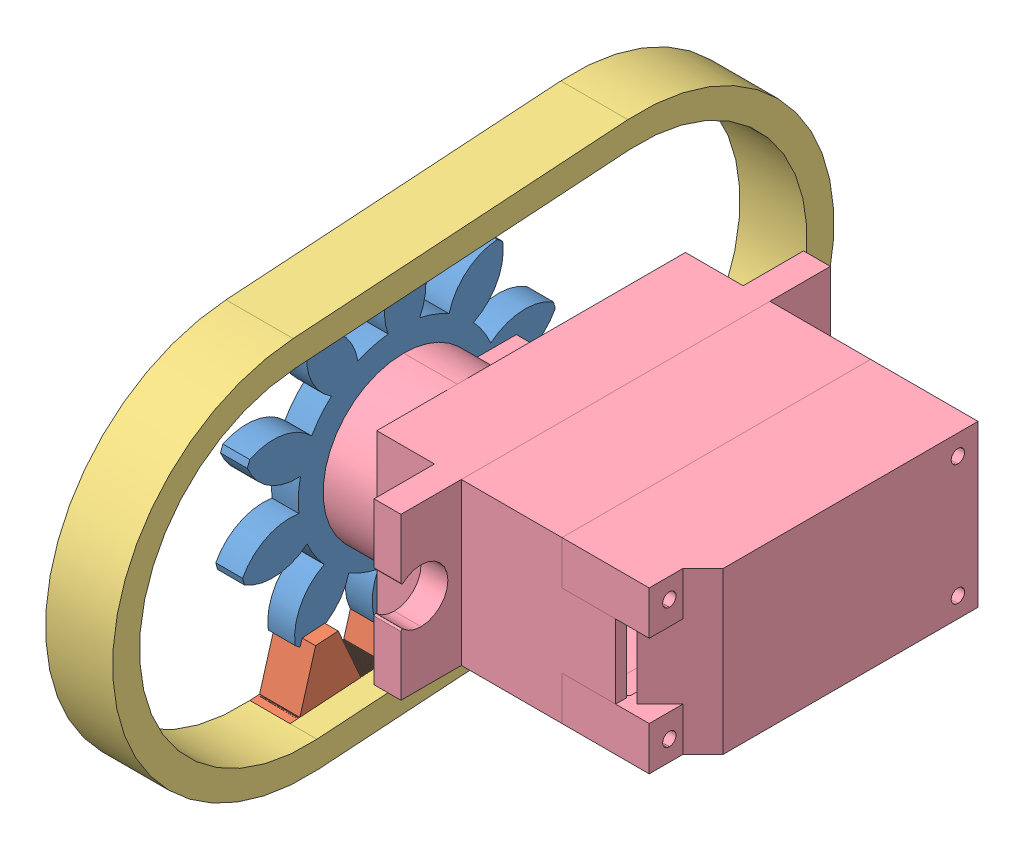
SolidWorks assembly RPServoAssy, configuration Default. Lengths in mm.
Overall size (28.15 32.3 55.59).
4 component instances, 4 part files, 8 mates.
Components (placement in the parent):
- spur gear_am-1: spur gear_am [Metric - Spur gear 2M 10T 20PA 2FW ---S10N75H50L5N] at (-18.7416 -7.9206 23.6757) x (-1 0 0) z (0 -0.356651 -0.934238) size (2 22.98 24)
- rack spur rectangular_am-1: rack spur rectangular_am [Metric - Rack-spur - rectangular 2M 20PA 3FW 2PH 25L---SAll] at (-20.7416 -19.3498 7.8364) x (0 -0.066207 0.997806) z (-1 0 0) size (25 4 3)
- loop-1: loop [Default] at (-15.7416 -8.5795 33.606) x (0 0.066207 -0.997806) z (0 0.997806 0.066207) size (53.8 5 28.8)
- ServoMotor-1: ServoMotor [Default] at (10.0485 10.7533 11.699) x (0 0 1) z (0 -1 0) size (32 28.15 12)
Mates (geometry in assembly coordinates):
- Coincident1: coincident aligned: plane of rack spur rectangular_am-1 through (-17.7416 -19.7702 14.9693) normal (0 0.997806 0.066207); plane of loop-1 through (-20.7416 -20.9523 32.785) normal (0 0.997806 0.066207)
- Coincident2: coincident aligned: plane of rack spur rectangular_am-1 through (-20.7416 -15.3586 8.1012) normal (-1 0 0); plane of loop-1 through (-20.7416 -8.5795 33.606) normal (-1 0 0)
- Coincident3: coincident anti-aligned: line of rack spur rectangular_am-1 through (-17.7416 -19.2971 7.8399) axis (-1 0 0); line of loop-1 through (-20.7416 -19.2971 7.8399) axis (1 0 0)
- Coincident5: coincident aligned: plane of spur gear_am-1 through (-20.7416 -7.9206 23.6757) normal (-1 0 0); plane of loop-1 through (-20.7416 -8.5795 33.606) normal (-1 0 0)
- Distance1: distance = 12.4 mm: plane of rack spur rectangular_am-1 through (-17.7416 -19.7702 14.9693) normal (0 0.997806 0.066207); cylinder of spur gear_am-1 through (-68.7416 -7.9206 23.6757) axis (1 0 0) radius 2.5
- RackPinionMate2: rack pinion = 20 mm: line of loop-1 through (-20.7416 -21.2928 7.7075) axis (0 -0.066207 0.997806); circle of spur gear_am-1
- Concentric1: concentric aligned: cylinder of spur gear_am-1 through (-68.7416 -7.9206 23.6757) axis (1 0 0) radius 2.5; cylinder of ServoMotor-1 through (-20.7416 -7.9206 23.6757) axis (1 0 0) radius 2.5
- Coincident6: coincident aligned: plane of spur gear_am-1 through (-20.7416 -7.9206 23.6757) normal (-1 0 0); plane of ServoMotor-1 through (-20.7416 -7.9206 23.6757) normal (-1 0 0)
